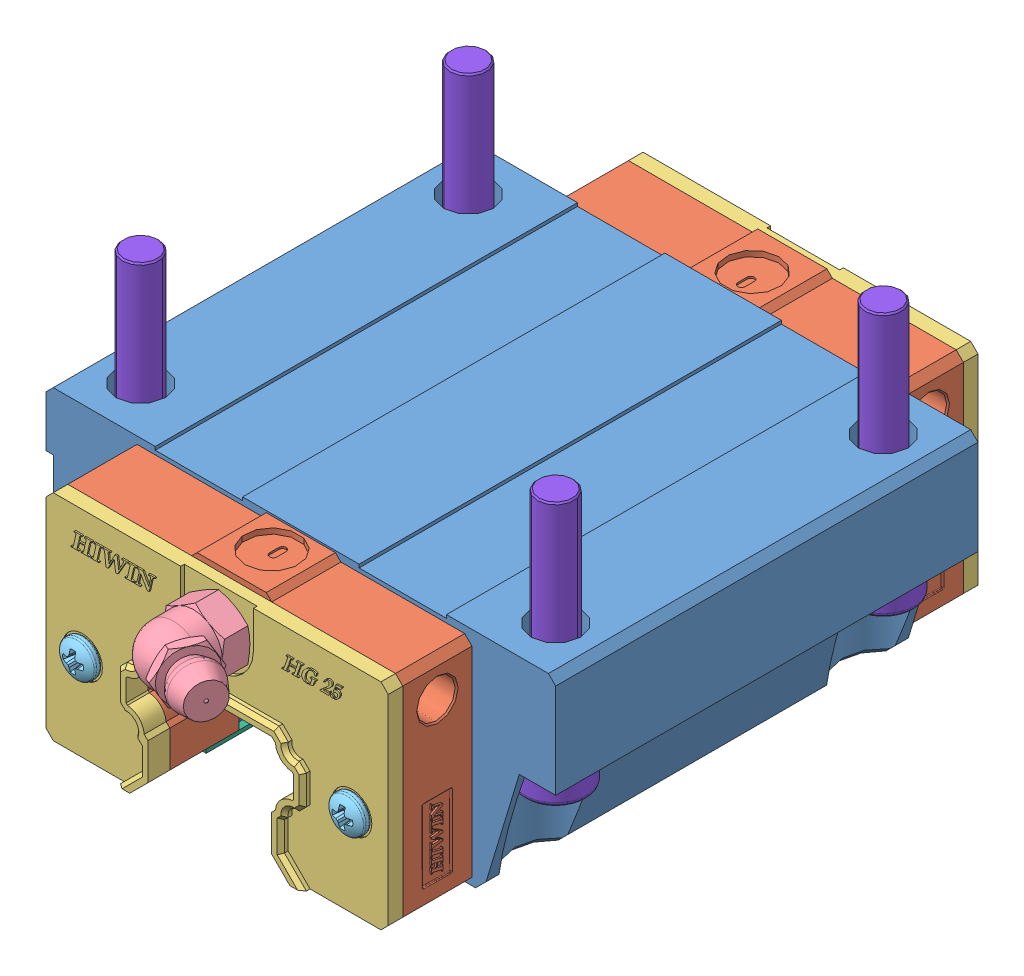
SolidWorks assembly Slider HIWIN Corporation-HGW-25-CC-DEFAULT, configuration Default. Lengths in mm.
Overall size (70 46.5 93.99).
17 component instances, 8 part files, 8 mates.
Components (placement in the parent):
- Slider HIWIN Corporation-HGW-25-CC-DEFAULT_HGW-25-CC BLOCK-1: Slider HIWIN Corporation-HGW-25-CC-DEFAULT_HGW-25-CC BLOCK [Default] at (10.7208 1.8351 -6.9039) size (70 30.5 58)
- Slider HIWIN Corporation-HGW-25-CC-DEFAULT_HG 25 End Cap-1: Slider HIWIN Corporation-HGW-25-CC-DEFAULT_HG 25 End Cap [Default] at (10.7208 -0.9149 -6.9039) x (-1 0 0) z (0 0 -1) size (47 30.25 9.5)
- Slider HIWIN Corporation-HGW-25-CC-DEFAULT_HG 25 End Cap-2: Slider HIWIN Corporation-HGW-25-CC-DEFAULT_HG 25 End Cap [Default] at (10.7208 -0.9149 51.0961) size (47 30.25 9.5)
- Slider HIWIN Corporation-HGW-25-CC-DEFAULT_HG-25 Wiper-1: Slider HIWIN Corporation-HGW-25-CC-DEFAULT_HG-25 Wiper [Default] at (0.8471 0.7746 62.5961) x (-1 0 0) z (0 0 -1) size (47 29.5 3)
- Slider HIWIN Corporation-HGW-25-CC-DEFAULT_HG-25 Wiper-2: Slider HIWIN Corporation-HGW-25-CC-DEFAULT_HG-25 Wiper [Default] at (20.5945 0.7746 -18.4039) size (47 29.5 3)
- Slider HIWIN Corporation-HGW-25-CC-DEFAULT_M6 Angle GN-1: Slider HIWIN Corporation-HGW-25-CC-DEFAULT_M6 Angle GN [Default] at (10.7208 -3.6649 20.5961) x (0 0 -1) z (1 0 0) size (19 9.24 12.74)
- Slider HIWIN Corporation-HGW-25-CC-DEFAULT_M2.6X12L Machine Screw-1: Slider HIWIN Corporation-HGW-25-CC-DEFAULT_M2.6X12L Machine Screw [Default] at (29.2208 13.8351 50.3961) size (5 5 13.76)
- Slider HIWIN Corporation-HGW-25-CC-DEFAULT_M2.6X12L Machine Screw-2: Slider HIWIN Corporation-HGW-25-CC-DEFAULT_M2.6X12L Machine Screw [Default] at (-7.7792 13.8351 50.3961) size (5 5 13.76)
- Slider HIWIN Corporation-HGW-25-CC-DEFAULT_M2.6X12L Machine Screw-3: Slider HIWIN Corporation-HGW-25-CC-DEFAULT_M2.6X12L Machine Screw [Default] at (-7.7792 13.8351 -6.2039) x (-0.923728 -0.383049 0) z (0 0 -1) size (5 5 13.76)
- Slider HIWIN Corporation-HGW-25-CC-DEFAULT_M2.6X12L Machine Screw-4: Slider HIWIN Corporation-HGW-25-CC-DEFAULT_M2.6X12L Machine Screw [Default] at (29.2208 13.8351 -6.2039) x (-0.923728 -0.383049 0) z (0 0 -1) size (5 5 13.76)
- Slider HIWIN Corporation-HGW-25-CC-DEFAULT_HG-25-C Bottom Seal-1: Slider HIWIN Corporation-HGW-25-CC-DEFAULT_HG-25-C Bottom Seal [Default] at (-6.2792 2.8351 54.0961) x (1 0 0) z (0 0 -1) size (7 1 70)
- Slider HIWIN Corporation-HGW-25-CC-DEFAULT_HG-25-C Bottom Seal-2: Slider HIWIN Corporation-HGW-25-CC-DEFAULT_HG-25-C Bottom Seal [Default] at (27.7208 2.8351 -9.9039) x (-1 0 0) z (0 0 1) size (7 1 70)
- Slider HIWIN Corporation-HGW-25-CC-DEFAULT_M6 Plug Screw-1: Slider HIWIN Corporation-HGW-25-CC-DEFAULT_M6 Plug Screw [Default] at (10.7208 26.3351 -15.3546) x (-0.923728 -0.383049 0) z (0 0 -1) size (6.5 6.5 7)
- hexagon socket head cap screws gb-1: hexagon socket head cap screws gb [GB_FASTENER_SCREWS_HSHCS M5X30-N] at (39.2208 13.3351 -0.4039) x (0 1 0) z (0 0 1) size (35 8.5 8.5)
- hexagon socket head cap screws gb-2: hexagon socket head cap screws gb [GB_FASTENER_SCREWS_HSHCS M5X30-N] at (39.2208 13.3351 44.5961) x (0 1 0) z (0 0 -1) size (35 8.5 8.5)
- hexagon socket head cap screws gb-3: hexagon socket head cap screws gb [GB_FASTENER_SCREWS_HSHCS M5X30-N] at (-17.7792 13.3351 44.5961) x (0 1 0) z (0 0 1) size (35 8.5 8.5)
- hexagon socket head cap screws gb-4: hexagon socket head cap screws gb [GB_FASTENER_SCREWS_HSHCS M5X30-N] at (-17.7792 13.3351 -0.4039) x (0 1 0) z (0 0 1) size (35 8.5 8.5)
Mates (geometry in assembly coordinates):
- Concentric1: concentric aligned: cylinder of Slider HIWIN Corporation-HGW-25-CC-DEFAULT_HGW-25-CC BLOCK-1 through (39.2208 34.245 -0.4039) axis (0 -1 0) radius 5.625; cylinder of hexagon socket head cap screws gb-1 through (39.2208 48.3351 -0.4039) axis (0 -1 0) radius 2.5
- Coincident1: coincident anti-aligned: plane of Slider HIWIN Corporation-HGW-25-CC-DEFAULT_HGW-25-CC BLOCK-1 through (45.7208 18.3351 51.0961) normal (0 -1 0); plane of hexagon socket head cap screws gb-1 through (39.2208 18.3351 -0.4039) normal (0 1 0)
- Concentric2: concentric aligned: cylinder of Slider HIWIN Corporation-HGW-25-CC-DEFAULT_HGW-25-CC BLOCK-1 through (39.2208 34.245 44.5961) axis (0 -1 0) radius 5.625; cylinder of hexagon socket head cap screws gb-2 through (39.2208 48.3351 44.5961) axis (0 -1 0) radius 2.5
- Coincident2: coincident anti-aligned: plane of Slider HIWIN Corporation-HGW-25-CC-DEFAULT_HGW-25-CC BLOCK-1 through (45.7208 18.3351 51.0961) normal (0 -1 0); plane of hexagon socket head cap screws gb-2 through (39.2208 18.3351 44.5961) normal (0 1 0)
- Concentric3: concentric aligned: cylinder of Slider HIWIN Corporation-HGW-25-CC-DEFAULT_HGW-25-CC BLOCK-1 through (-17.7792 1.8351 44.5961) axis (0 -1 0) radius 3.4; cylinder of hexagon socket head cap screws gb-3 through (-17.7792 48.3351 44.5961) axis (0 -1 0) radius 2.5
- Coincident3: coincident anti-aligned: plane of Slider HIWIN Corporation-HGW-25-CC-DEFAULT_HGW-25-CC BLOCK-1 through (-19.2792 18.3351 51.0961) normal (0 -1 0); plane of hexagon socket head cap screws gb-3 through (-17.7792 18.3351 44.5961) normal (0 1 0)
- Concentric4: concentric aligned: cylinder of Slider HIWIN Corporation-HGW-25-CC-DEFAULT_HGW-25-CC BLOCK-1 through (-17.7792 1.8351 -0.4039) axis (0 -1 0) radius 3.4; cylinder of hexagon socket head cap screws gb-4 through (-17.7792 48.3351 -0.4039) axis (0 -1 0) radius 2.5
- Coincident4: coincident anti-aligned: plane of Slider HIWIN Corporation-HGW-25-CC-DEFAULT_HGW-25-CC BLOCK-1 through (-19.2792 18.3351 51.0961) normal (0 -1 0); plane of hexagon socket head cap screws gb-4 through (-17.7792 18.3351 -0.4039) normal (0 1 0)
